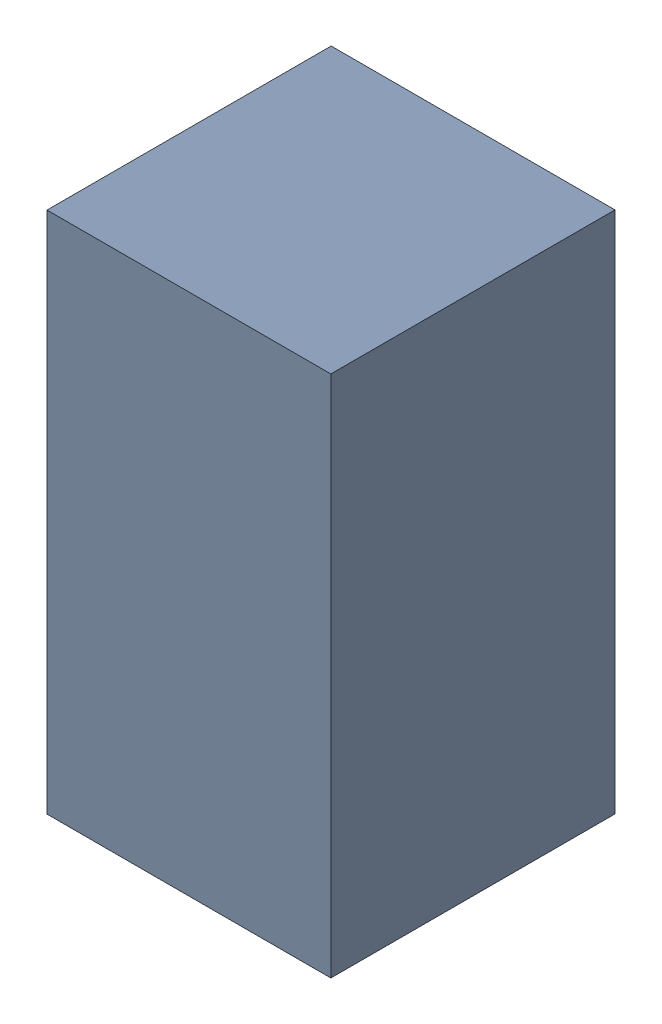
SolidWorks assembly L1, configuration Default. Lengths in mm.
Overall size (0.95 1.75 0.95).
3 component instances, 2 part files, 0 mates.
Components (placement in the parent):
- 1737246832-1: 1737246832 [Default] at (15.25 21.475 0) size (0.95 1.75 0.95)
  - Extruded-35-1: Extruded-35 [Default] at origin size (0.95 1.75 0.95)
- L0603-1: L0603 [Default] at (15.6501 20.6749 0) x (0 1 0) z (1 0 0) size (1.6 0.5 0.8)
